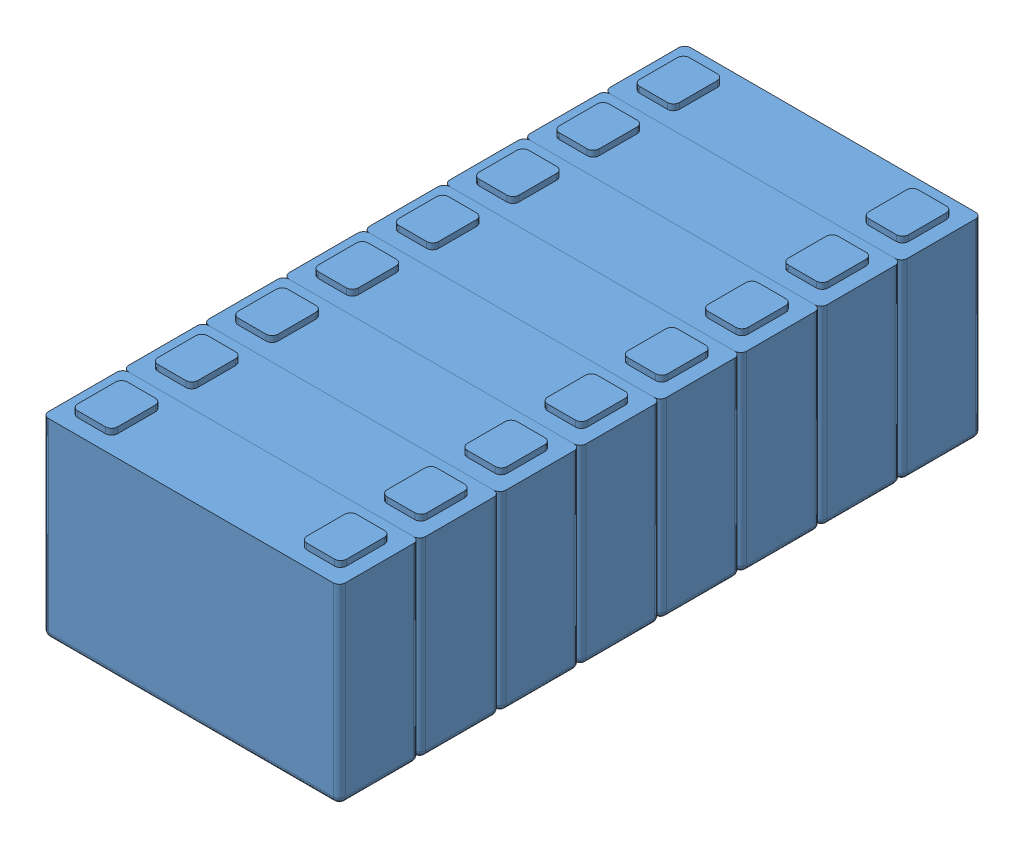
SolidWorks assembly Battery_Pack_8No_V2, configuration Default. Lengths in mm.
Overall size (149 99 322.4).
8 component instances, 1 part files, 0 mates.
Components (placement in the parent):
- Li_Battery_WSP-LFP3914895-50Ah-2: Li_Battery_WSP-LFP3914895-50Ah [Default] at origin size (149 99 40.3)
- Li_Battery_WSP-LFP3914895-50Ah-3: Li_Battery_WSP-LFP3914895-50Ah [Default] at (0 0 -40.3) size (149 99 40.3)
- Li_Battery_WSP-LFP3914895-50Ah-4: Li_Battery_WSP-LFP3914895-50Ah [Default] at (0 0 -80.6) size (149 99 40.3)
- Li_Battery_WSP-LFP3914895-50Ah-5: Li_Battery_WSP-LFP3914895-50Ah [Default] at (0 0 -120.9) size (149 99 40.3)
- Li_Battery_WSP-LFP3914895-50Ah-6: Li_Battery_WSP-LFP3914895-50Ah [Default] at (0 0 40.3) size (149 99 40.3)
- Li_Battery_WSP-LFP3914895-50Ah-7: Li_Battery_WSP-LFP3914895-50Ah [Default] at (0 0 80.6) size (149 99 40.3)
- Li_Battery_WSP-LFP3914895-50Ah-8: Li_Battery_WSP-LFP3914895-50Ah [Default] at (0 0 120.9) size (149 99 40.3)
- Li_Battery_WSP-LFP3914895-50Ah-9: Li_Battery_WSP-LFP3914895-50Ah [Default] at (0 0 161.2) size (149 99 40.3)
